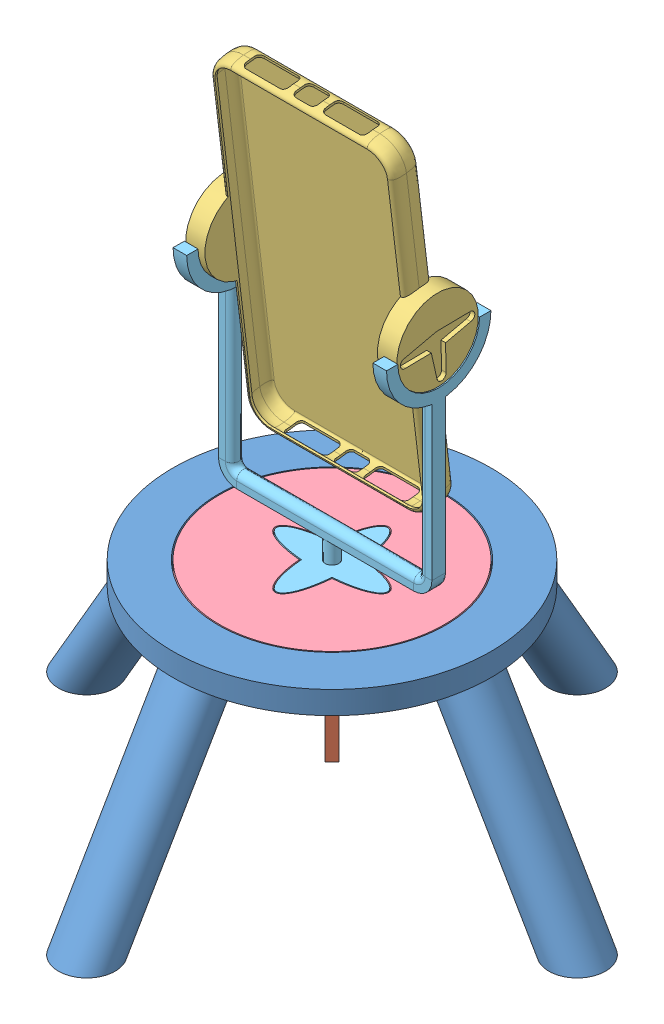
SolidWorks assembly Assem_2, configuration Default. Lengths in mm.
Overall size (240.97 280.93 240.97).
5 component instances, 5 part files, 9 mates.
Components (placement in the parent):
- OuterBase-1: OuterBase [Default] at (127.0961 70.7107 47.3121) x (1 0 0) z (0 1 0) size (240.97 240.97 96.73)
- ServoSupport_2-1: ServoSupport_2 [Default] at (128.8638 45.2107 45.5443) x (0.707107 0 0.707107) z (0 -1 0) size (115 115 28.5)
- Holder-1: Holder [Default] at (127.1056 187.7107 47.3121) x (0 0.118444 -0.992961) z (1 0 0) size (36 151.19 92.98)
- Base_2-1: Base_2 [Default] at (127.0961 80.7107 47.3121) x (1 0 0) z (0 0 -1) size (99 5 99)
- Stand_2-1: Stand_2 [Default] at (127.0961 78.7107 47.3121) size (94 124 49)
Mates (geometry in assembly coordinates):
- Coincident34: coincident anti-aligned: plane of OuterBase-1 through (127.0961 75.7107 47.3121) normal (0 1 0); plane of Base_2-1 through (127.0961 75.7107 47.3121) normal (0 -1 0)
- Concentric1: concentric anti-aligned: cylinder of OuterBase-1 through (127.0961 80.7107 47.3121) axis (0 -1 0) radius 50; cylinder of Base_2-1 through (127.0961 75.7107 47.3121) axis (0 1 0) radius 49.5
- Coincident35: coincident anti-aligned: plane of Base_2-1 through (127.0961 78.7107 47.3121) normal (0 1 0); plane of Stand_2-1 through (127.0961 78.7107 47.3121) normal (0 -1 0)
- Concentric2: concentric aligned: cylinder of OuterBase-1 through (127.0961 80.7107 47.3121) axis (0 -1 0) radius 70; cylinder of Stand_2-1 through (127.0961 89.7107 47.3121) axis (0 -1 0) radius 3
- Concentric3: concentric aligned: cylinder of Holder-1 through (173.5961 187.7107 47.3121) axis (-1 0 0) radius 18; cylinder of Stand_2-1 through (225.5256 187.7107 47.3121) axis (-1 0 0) radius 18
- Distance2: distance = 0.5 mm aligned: plane of Holder-1 through (173.5961 187.7107 47.3121) normal (1 0 0); plane of Stand_2-1 through (174.0961 167.7107 50.3121) normal (1 0 0)
- Coincident38: coincident anti-aligned: plane of OuterBase-1 through (127.0961 72.7107 47.3121) normal (0 -1 0); plane of ServoSupport_2-1 through (166.1637 72.7107 83.1977) normal (0 1 0)
- Distance3: distance = 0.25 mm anti-aligned: plane of ServoSupport_2-1 through (130.4548 45.2107 47.1353) normal (0.707107 0 0.707107); plane of OuterBase-1 through (128.8638 72.7107 49.0798) normal (-0.707107 0 -0.707107)
- Distance4: distance = 0.25 mm anti-aligned: plane of ServoSupport_2-1 through (125.5051 45.2107 48.9031) normal (-0.707107 0 0.707107); plane of OuterBase-1 through (125.3283 72.7107 49.0798) normal (0.707107 0 -0.707107)
